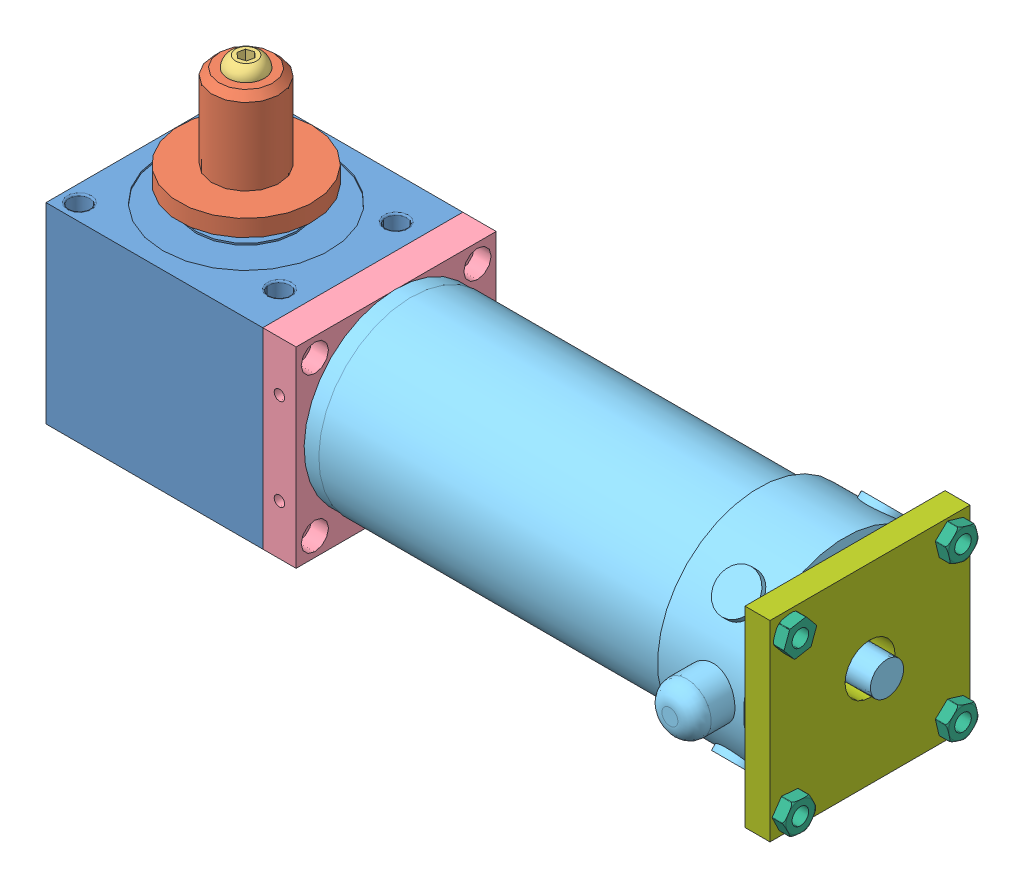
SolidWorks assembly TWM3RS+S28400, configuration Default. Lengths in mm.
Overall size (282.19 141.98 116.77).
22 component instances, 8 part files, 21 mates.
Components (placement in the parent):
- GearBox-1: GearBox [Default] at (-41.9919 13.5713 12.9384) size (82.55 73.03 76.2)
- Shaft-1: Shaft [Default] at (-3.8919 21.5723 51.0384) x (0 1 0) z (-0.998642 0 -0.052093) size (109.47 50.8 50.8)
- 5-16 Buttonhead-1: 5-16 Buttonhead [Default] at (-3.8919 124.6963 51.0384) x (0 1 0) z (-0.948972 0 0.315359) size (10.57 13.89 13.89)
- Motor_Plate-1: Motor_Plate [Default] at (53.2581 86.5963 12.9384) x (-1 0 0) z (0 0 -1) size (12.7 73.03 76.2)
- s28400mag-1: s28400mag [Default] at (224.2001 51.6713 51.0434) x (0 -0.707107 -0.707107) z (-1 0 0) size (82.57 82.57 225.04)
- Support Stud-1: Support Stud [Default] at (27.8581 79.4589 82.001) x (0 0.147414 0.989075) z (-1 0 0)
  - 1-4 Stud-1: 1-4 Stud [Stud .25 X 1] at origin (suppressed, hidden)
  - 1-4 20 Nut-2: 1-4 20 Nut [Default] at (0 0 -27.6225) (suppressed, hidden)
- Support Stud-2: Support Stud [Default] at (27.8581 20.7087 82.001) x (0 0.147414 0.989075) z (-1 0 0)
  - 1-4 Stud-1: 1-4 Stud [Stud .25 X 1] at origin (suppressed, hidden)
  - 1-4 20 Nut-2: 1-4 20 Nut [Default] at (0 0 -27.6225) (suppressed, hidden)
- Support Stud-3: Support Stud [Default] at (27.8581 20.7087 20.0758) x (0 0.147414 0.989075) z (-1 0 0)
  - 1-4 Stud-1: 1-4 Stud [Stud .25 X 1] at origin (suppressed, hidden)
  - 1-4 20 Nut-2: 1-4 20 Nut [Default] at (0 0 -27.6225) (suppressed, hidden)
- Support Stud-4: Support Stud [Default] at (27.8581 79.4589 20.0758) x (0 0.707019 0.707195) z (-1 0 0)
  - 1-4 Stud-1: 1-4 Stud [Stud .25 X 1] at origin (suppressed, hidden)
  - 1-4 20 Nut-2: 1-4 20 Nut [Default] at (0 0 -27.6225) (suppressed, hidden)
- 1-4 20 Nut-1: 1-4 20 Nut [Default] at (235.9476 20.7087 82.001) x (0 0.826886 -0.56237) z (1 0 0)
- 1-4 20 Nut-2: 1-4 20 Nut [Default] at (235.9476 79.4589 20.0758) x (0 0.972148 0.234368) z (1 0 0)
- 1-4 20 Nut-3: 1-4 20 Nut [Default] at (235.9476 79.4589 82.001) x (0 0.171604 -0.985166) z (-1 0 0)
- 1-4 20 Nut-4: 1-4 20 Nut [Default] at (235.9476 20.7087 20.0758) x (0 0.680983 -0.7323) z (1 0 0)
- Rear Clamp Plate-1: Rear Clamp Plate [Default] at (224.2001 86.5963 89.1384) size (9.53 73.03 76.2)
Mates (geometry in assembly coordinates):
- Concentric1: concentric aligned: cylinder of GearBox-1 through (-3.8919 29.4463 51.0384) axis (0 1 0) radius 11.1125; cylinder of Shaft-1 through (-3.8919 131.0463 51.0384) axis (0 1 0) radius 11.1125
- Coincident1: coincident aligned: plane of GearBox-1 through (-41.9919 86.5963 89.1384) normal (0 1 0); circle of Shaft-1
- Concentric2: concentric anti-aligned: cylinder of Shaft-1 through (-3.8919 97.2643 51.0384) axis (0 1 0) radius 3.9688; circle of 5-16 Buttonhead-1
- Coincident2: coincident anti-aligned: plane of Shaft-1 through (-3.2303 131.0463 38.3557) normal (0 1 0); plane of 5-16 Buttonhead-1 through (-5.1435 131.0463 47.2722) normal (0 -1 0)
- Coincident6: coincident aligned: line of GearBox-1 through (40.5581 86.5963 12.9384) axis (0 -1 0); line of Motor_Plate-1 through (40.5581 86.5963 12.9384) axis (0 -1 0)
- Coincident7: coincident anti-aligned: line of GearBox-1 through (40.5581 13.5713 89.1384) axis (0 0 -1); line of Motor_Plate-1 through (40.5581 13.5713 12.9384) axis (0 0 1)
- Concentric7: concentric anti-aligned: circle of Motor_Plate-1; circle of Support Stud-1/1-4 Stud-1
- Coincident10: coincident anti-aligned: plane of Motor_Plate-1 through (53.2581 13.5713 12.9384) normal (1 0 0); plane of Support Stud-1/1-4 20 Nut-2 through (53.2581 85.3661 84.3307) normal (-1 0 0)
- Concentric8: concentric anti-aligned: circle of Motor_Plate-1; circle of Support Stud-2/1-4 Stud-1
- Coincident11: coincident anti-aligned: plane of Motor_Plate-1 through (53.2581 13.5713 12.9384) normal (1 0 0); plane of Support Stud-2/1-4 20 Nut-2 through (53.2581 26.6159 84.3307) normal (-1 0 0)
- Concentric9: concentric anti-aligned: circle of Motor_Plate-1; circle of Support Stud-3/1-4 Stud-1
- Concentric10: concentric anti-aligned: circle of Motor_Plate-1; circle of Support Stud-4/1-4 Stud-1
- Coincident12: coincident anti-aligned: plane of Motor_Plate-1 through (53.2581 13.5713 12.9384) normal (1 0 0); plane of Support Stud-4/1-4 20 Nut-2 through (53.2581 85.5927 18.4331) normal (-1 0 0)
- Coincident13: coincident anti-aligned: plane of Motor_Plate-1 through (53.2581 13.5713 12.9384) normal (1 0 0); plane of Support Stud-3/1-4 20 Nut-2 through (53.2581 26.6159 22.4055) normal (-1 0 0)
- Concentric14: concentric aligned: circle of Support Stud-2/1-4 Stud-1; circle of 1-4 20 Nut-1
- Concentric15: concentric anti-aligned: circle of Support Stud-1/1-4 Stud-1; circle of 1-4 20 Nut-3
- Concentric16: concentric aligned: circle of Support Stud-4/1-4 Stud-1; circle of 1-4 20 Nut-2
- Concentric17: concentric aligned: circle of Support Stud-3/1-4 Stud-1; circle of 1-4 20 Nut-4
- Coincident14: coincident anti-aligned: plane of s28400mag-1 through (224.2001 51.6713 51.0434) normal (1 0 0); plane of Rear Clamp Plate-1 through (224.2001 13.5713 89.1384) normal (-1 0 0)
- Concentric22: concentric aligned: cylinder of Support Stud-3/1-4 Stud-1 through (243.7581 20.7087 20.0758) axis (-1 0 0) radius 3.175; circle of Rear Clamp Plate-1
- Concentric23: concentric aligned: cylinder of Support Stud-1/1-4 Stud-1 through (243.7581 79.4589 82.001) axis (-1 0 0) radius 3.175; circle of Rear Clamp Plate-1
